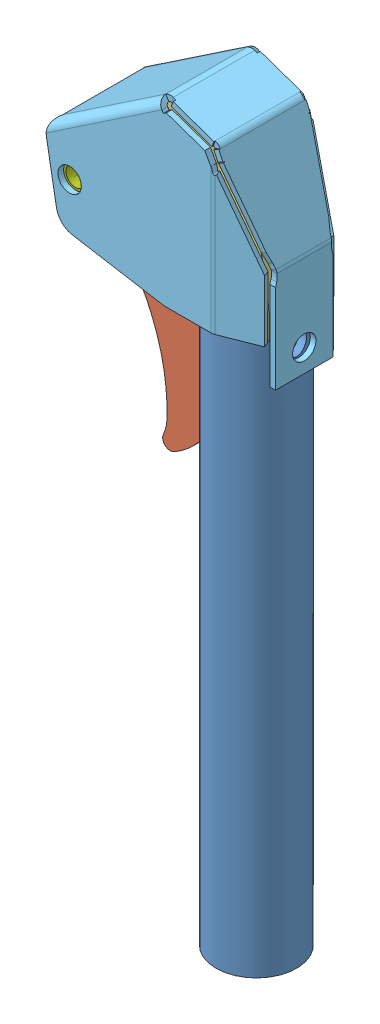
SolidWorks assembly 000 - Газулька, configuration 00. Lengths in mm.
Overall size (103.18 265.64 26.01).
9 component instances, 8 part files, 14 mates.
Components (placement in the parent):
- Труба основа-1: Труба основа [--] at origin size (21.3 150 21.3) (hidden)
- Курок-1: Курок [--] at (-36.3091 13.3669 0) x (0.932086 0.362238 0) z (0 0 1) size (51.69 73.77 6)
- Опора курка-1: Опора курка [--] at (0 0 3.25) size (56.96 43.45 4)
- Вставка в трубу-1: Вставка в трубу [--] at origin size (17.24 50 17.3)
- Кожух-1: Кожух [--] at origin size (56.43 56.76 26.01)
- Ось курка-1: Ось курка [--] at (-36.3091 13.3669 7.25) size (13 13 23) (hidden)
- Ось курка-2: Ось курка [00] at (-36.3091 13.3669 7.25) size (13 13 23)
  - Ось-1: Ось [--] at origin size (13 13 23)
  - Шайба оси-1: Шайба оси [--] at origin size (13 13 4.25)
Mates (geometry in assembly coordinates):
- Совпадение1: coincident: point of Курок-1; point of assembly
- Совпадение2: coincident: plane of Курок-1 through (-36.3091 13.3669 0) normal (0 0 1); line of assembly
- Совпадение3: coincident: plane of Курок-1 through (-36.3091 13.3669 0) normal (0.932086 0.362238 0); line of assembly
- Перпендикулярность1: perpendicular: plane of Курок-1 through (-36.3091 13.3669 0) normal (-0.362238 0.932086 0); plane of assembly through (0 0 0) normal (0 0 1)
- Расстояние1: distance = 0.25 mm: plane of Опора курка-1 through (0 0 3.25) normal (0 0 1); plane of Курок-1 through (-19.7449 -43.334 3) normal (0 0 1)
- Совпадение4: coincident: plane of Опора курка-1 through (0 0 3.25) normal (0 1 0); plane of assembly through (0 0 0) normal (0 1 0)
- Совпадение5: coincident: plane of Опора курка-1 through (0 0 3.25) normal (1 0 0); plane of assembly through (0 0 0) normal (1 0 0)
- Совпадение6: coordinate: unknown of ?
- Совпадение7: coincident: plane of Опора курка-1 through (-52.2585 0 7.25) normal (0 0 1); plane of Ось курка-1 through (-36.3091 13.3669 7.25) normal (0 0 1)
- Параллельность1: parallel: plane of Ось курка-1 through (-36.3091 13.3669 7.25) normal (0 1 0); plane of assembly through (0 0 0) normal (0 1 0)
- Совпадение8: coincident: plane of ? through (-36.3091 13.3669 7.25) normal (0 1 0)
- Совпадение9: coincident: plane of ? through (-36.3091 13.3669 7.25) normal (1 0 0)
- Концентричный1: concentric: cylinder of Ось курка-1 through (-36.3091 13.3669 11.5) axis (0 0 1) radius 2.5; cylinder of Ось курка-2/Ось-1 through (-36.3091 13.3669 11.5) axis (0 0 1) radius 2.5
- Совпадение10: coincident: plane of Кожух-1 through (0 0 11.5) normal (0 0 -1); plane of Ось курка-2/Ось-1 through (-36.3091 13.3669 11.5) normal (0 0 1)
